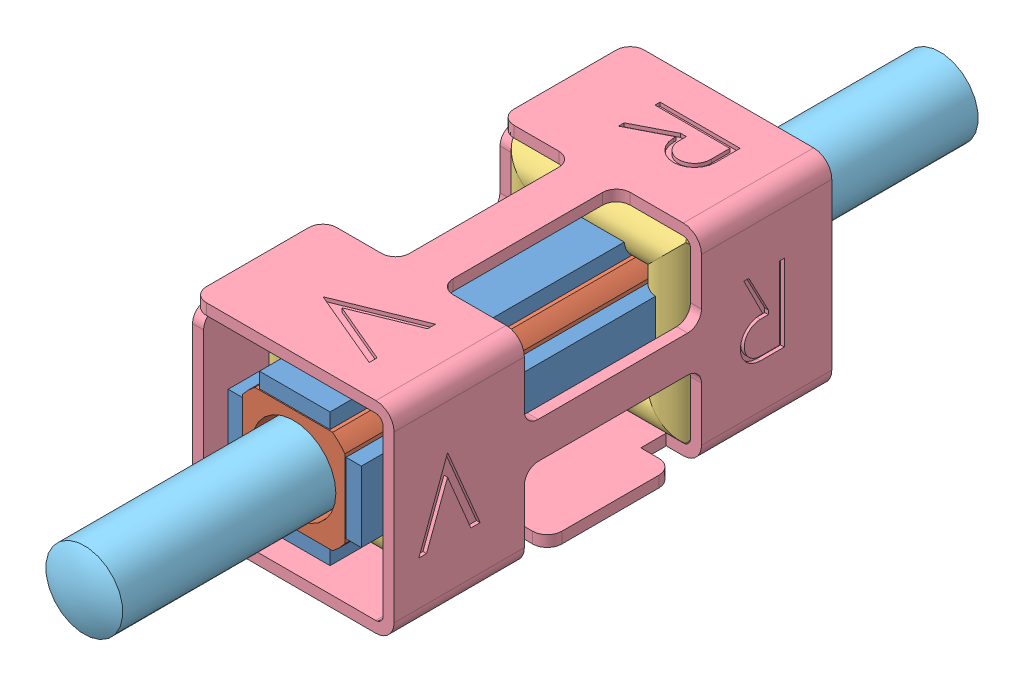
SolidWorks assembly 5910357824_1, configuration Standard. Lengths in mm.
Overall size (2.77 2.77 12).
11 component instances, 5 part files, 0 mates.
Components (placement in the parent):
- 02356-3-0000-1: 02356-3-0000 [Default] at (-0.0043 -0.0117 0.0036) size (1.83 1.83 6)
  - 02094-0-0000-1: 02094-0-0000 [Default] at (53.8621 -453.2709 1) x (0 -1 0) z (-1 0 0) size (0.97 5.97 0.21)
  - 02094-0-0000-2: 02094-0-0000 [Default] at (55.2721 -453.2709 1) x (0 -1 0) z (1 0 0) size (0.97 5.97 0.21)
  - 01594-0-0000_drawing view-1: 01594-0-0000_drawing view [Default] at (54.5671 -453.2709 1) size (1.41 1.41 6)
  - 02094-0-0000-3: 02094-0-0000 [Default] at (54.5671 -453.9759 1) x (1 0 0) z (0 -1 0) size (0.97 5.97 0.21)
  - 02094-0-0000-4: 02094-0-0000 [Default] at (54.5671 -452.5659 1) x (1 0 0) z (0 1 0) size (0.97 5.97 0.21)
- 02914-3-0000_BENT-1: 02914-3-0000_BENT [Default] at (6.5476 -454.5988 11.0929) x (-1 0 0) z (0 -1 0) size (2.77 6.02 2.77)
  - 02559-0-0000_WRAPPED-1: 02559-0-0000_WRAPPED [Default] at (-46.7822 8.4293 -2.5496) x (0 1 0) z (0 0 1) size (1.23 2.47 2.48)
  - 02915-0-0000_Correct Wrap-1: 02915-0-0000_Correct Wrap [Default] at (-56.4542 13.0993 2.6363) x (1 0 0) z (0 0 -1) size (2.77 6.02 2.77)
  - 02559-0-0000_WRAPPED-2: 02559-0-0000_WRAPPED [Default] at (-46.7822 11.7593 -2.5496) x (0 1 0) z (0 0 1) size (1.23 2.47 2.48)
- 01593-0-1012_MODEL-1: 01593-0-1012_MODEL [Default] at (54.5629 -453.2826 7.0036) x (-0.809258 0.587453 0) z (0 0 1) size (1.11 1.08 12)
